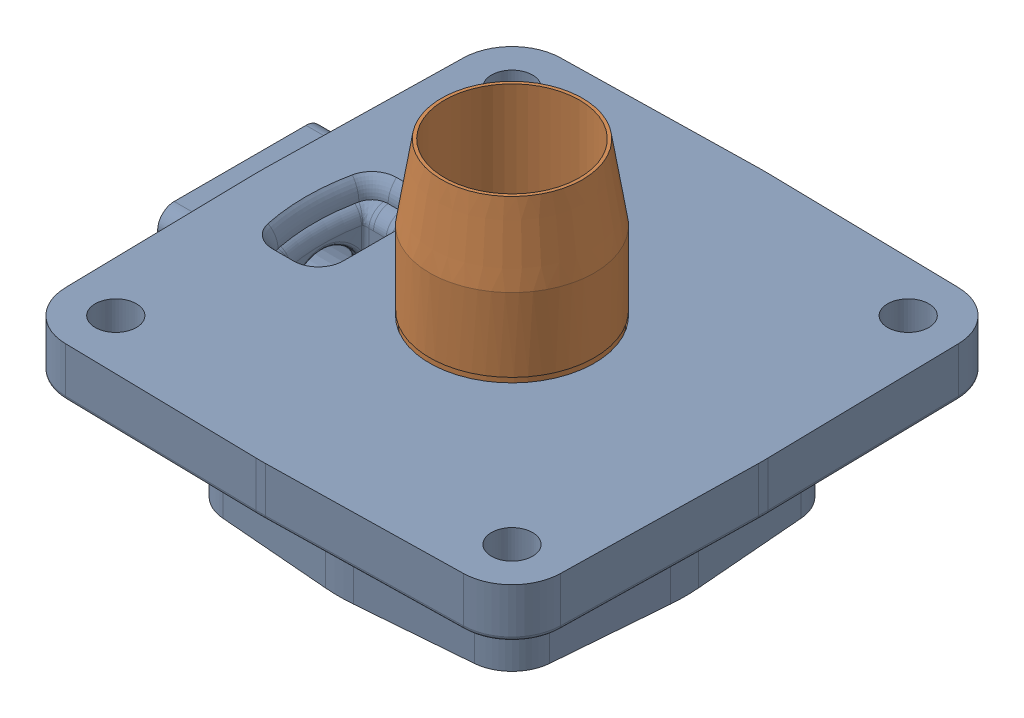
SolidWorks assembly BASE-F29DC-SL, configuration Default. Lengths in mm.
Overall size (100.81 59.66 96.84).
2 component instances, 2 part files, 0 mates.
Components (placement in the parent):
- BASE-F29DC-1: BASE-F29DC [Default] at origin size (100.81 30.18 96.84)
- SLEEVE-33-1: SLEEVE-33 [Default] at (0 44.5707 0) x (-1 0 0) z (0 0 1) size (31.75 38.89 31.75)
